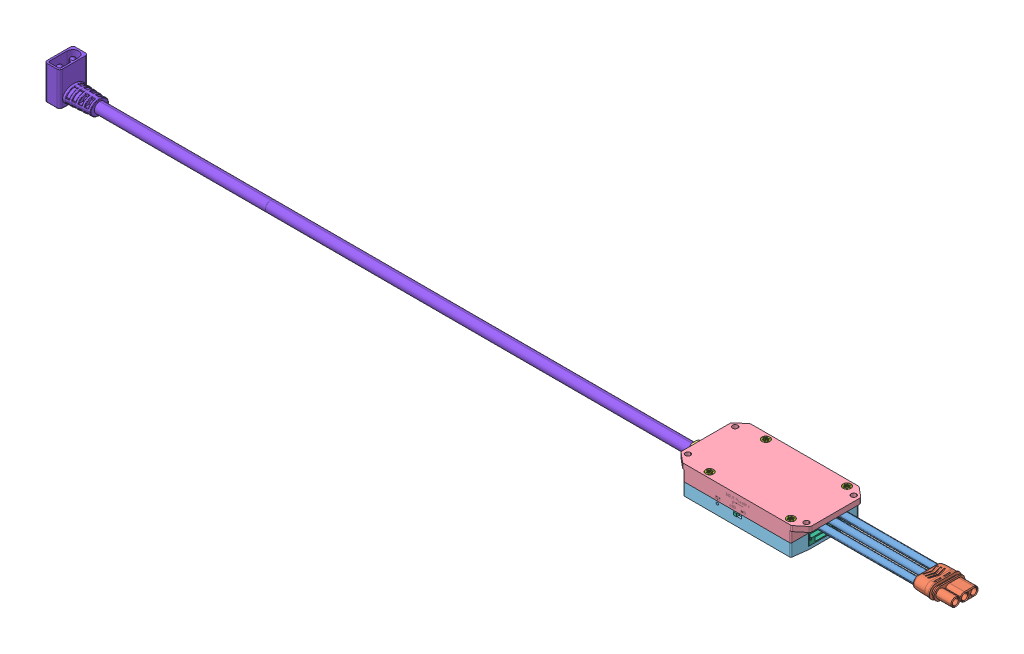
SolidWorks assembly C620无刷电机调速器, configuration 默认. Lengths in mm.
Overall size (345.36 15.69 26.13).
15 component instances, 8 part files, 0 mates.
Components (placement in the parent):
- C620无刷电机调速器.STEP-1: C620无刷电机调速器.STEP [Default] at origin size (345.36 15.69 26.13)
  - 9.STEP-1: 9.STEP [Default] at (63.0501 2 0) x (0 0 1) z (1 0 0) size (12.31 5.31 60.01)
    - 14.STEP-1: 14.STEP [默认] at (4 0 -0.7) size (2.5 2.5 50)
    - 14.STEP-2: 14.STEP [默认] at (0 0 -0.7) x (0.422263 0.906473 0) z (0 0 1) size (2.5 2.5 50)
    - 14.STEP-3: 14.STEP [默认] at (-4 0 -0.7) size (2.5 2.5 50)
    - 1.STEP-1: 1.STEP [默认] at (-18.7519 0 2.7064) x (-1 0 0) z (0 0 1) size (12.31 5.31 14.5)
  - 6.STEP-1: 6.STEP [默认] at (-2.2 39.826 -7.4409) x (0 -0.431667 0.902033) z (-1 0 0) size (8.67 8.67 10.5)
  - 7.STEP-1: 7.STEP [默认] at (-1.7 0.6 0) size (49.4 6 25.8)
  - 8.STEP-1: 8.STEP [默认] at (-1.7 -0.6 0) x (0 -1 0) z (0 0 1) size (6.5 41 25.8)
  - 2.STEP-1: 2.STEP [默认] at (15.6004 -0.6014 9.8) x (0 0 -1) z (0 1 0) size (24.83 40.8 4.35)
  - 5.STEP-1: 5.STEP [默认] at (16.6 -3.6 -10.7) x (-0.36263 0 0.931933) z (-0.931933 0 -0.36263) size (3 9 3)
  - 5.STEP-2: 5.STEP [默认] at (16.6 -3.6 10.7) size (3 9 3)
  - 5.STEP-3: 5.STEP [默认] at (-14.3 -3.6 10.7) size (3 9 3)
  - 5.STEP-4: 5.STEP [默认] at (-14.3 -3.6 -10.7) size (3 9 3)
  - 10.STEP-1: 10.STEP [默认] at (-177.4931 0.4104 -3.9137) x (1 0 0) z (0 -1 0) size (250.81 10.82 13.76)
